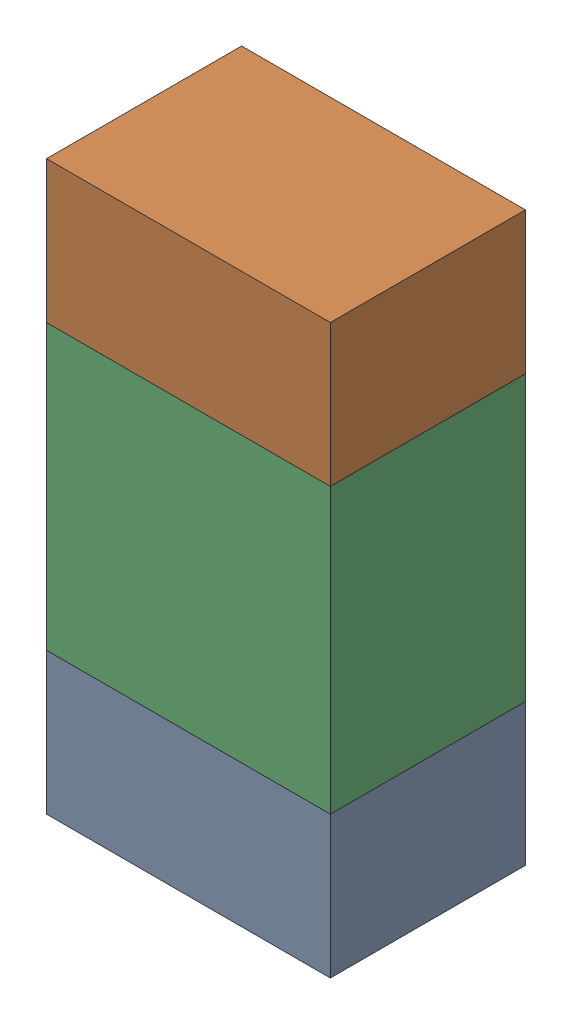
SolidWorks assembly R47, configuration ﾃﾞﾌｫﾙﾄ. Lengths in mm.
Overall size (0.8 1.6 0.55).
6 component instances, 2 part files, 0 mates.
Components (placement in the parent):
- 689261784-1: 689261784 [ﾃﾞﾌｫﾙﾄ] at (40.3226 15.2751 -1.7503) size (0.8 0.4 0.55)
  - Extruded_34-1: Extruded_34 [ﾃﾞﾌｫﾙﾄ] at origin size (0.8 0.4 0.55)
- 689261784-2: 689261784 [ﾃﾞﾌｫﾙﾄ] at (40.3226 16.4751 -1.7503) size (0.8 0.4 0.55)
  - Extruded_34-1: Extruded_34 [ﾃﾞﾌｫﾙﾄ] at origin size (0.8 0.4 0.55)
- 689261648-1: 689261648 [ﾃﾞﾌｫﾙﾄ] at (40.3226 15.875 -1.7503) size (0.8 0.8 0.55)
  - Extruded_33-1: Extruded_33 [ﾃﾞﾌｫﾙﾄ] at origin size (0.8 0.8 0.55)
